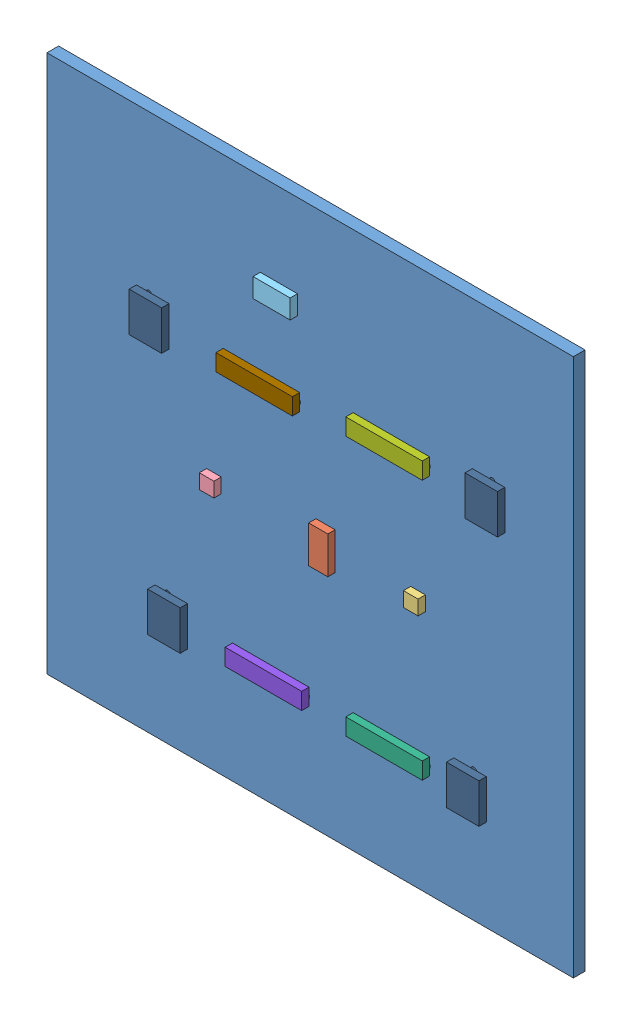
SolidWorks assembly untitled, configuration Default. Lengths in mm.
Overall size (72.06 73.65 2.6).
13 component instances, 10 part files, 0 mates.
Components (placement in the parent):
- untitled-1: untitled [Default] at origin size (72.06 73.65 1.6)
- JP1_JP1_JP1-1: JP1_JP1_JP1 [Default] at (48.26 34.29 1.6) x (-1 0 0) z (0 0 1) size (2.62 5.08 1)
- 1X1BIGPOGO_JP2_1X1BIGPOGO-1: 1X1BIGPOGO_JP2_1X1BIGPOGO [Default] at (60.96 34.29 1.6) size (2 2 1)
- 1X1BIGPOGO_JP3_1X1BIGPOGO-1: 1X1BIGPOGO_JP3_1X1BIGPOGO [Default] at (33.02 34.29 1.6) size (2 2 1)
- JP1_JP4_JP1-1: JP1_JP4_JP1 [Default] at (41.91 60.96 1.6) x (0 1 0) z (0 0 1) size (2.62 5.08 1)
- 0805THM_R1_0805THM-1: 0805THM_R1_0805THM [Default] at (57.15 15.24 1.6) size (10.46 2.29 1)
- 0805THM_R2_0805THM-1: 0805THM_R2_0805THM [Default] at (57.15 50.8 1.6) size (10.46 2.29 1)
- 0805THM_R3_0805THM-1: 0805THM_R3_0805THM [Default] at (40.64 15.24 1.6) size (10.46 2.29 1)
- 0805THM_R4_0805THM-1: 0805THM_R4_0805THM [Default] at (39.37 49.53 1.6) size (10.46 2.29 1)
- TO92EBCOVAL_2N2222-1: TO92EBCOVAL_2N2222 [Default] at (67.31 15.24 1.6) x (0 1 0) z (0 0 1) size (5.4 4.44 1)
- TO92EBCOVAL_2N2222-2: TO92EBCOVAL_2N2222 [Default] at (27.94 15.24 1.6) x (0 -1 0) z (0 0 1) size (5.4 4.44 1)
- TO92EBCOVAL_2N2222-3: TO92EBCOVAL_2N2222 [Default] at (25.4 49.53 1.6) x (0 -1 0) z (0 0 1) size (5.4 4.44 1)
- TO92EBCOVAL_2N2222-4: TO92EBCOVAL_2N2222 [Default] at (69.85 50.8 1.6) x (0 1 0) z (0 0 1) size (5.4 4.44 1)
